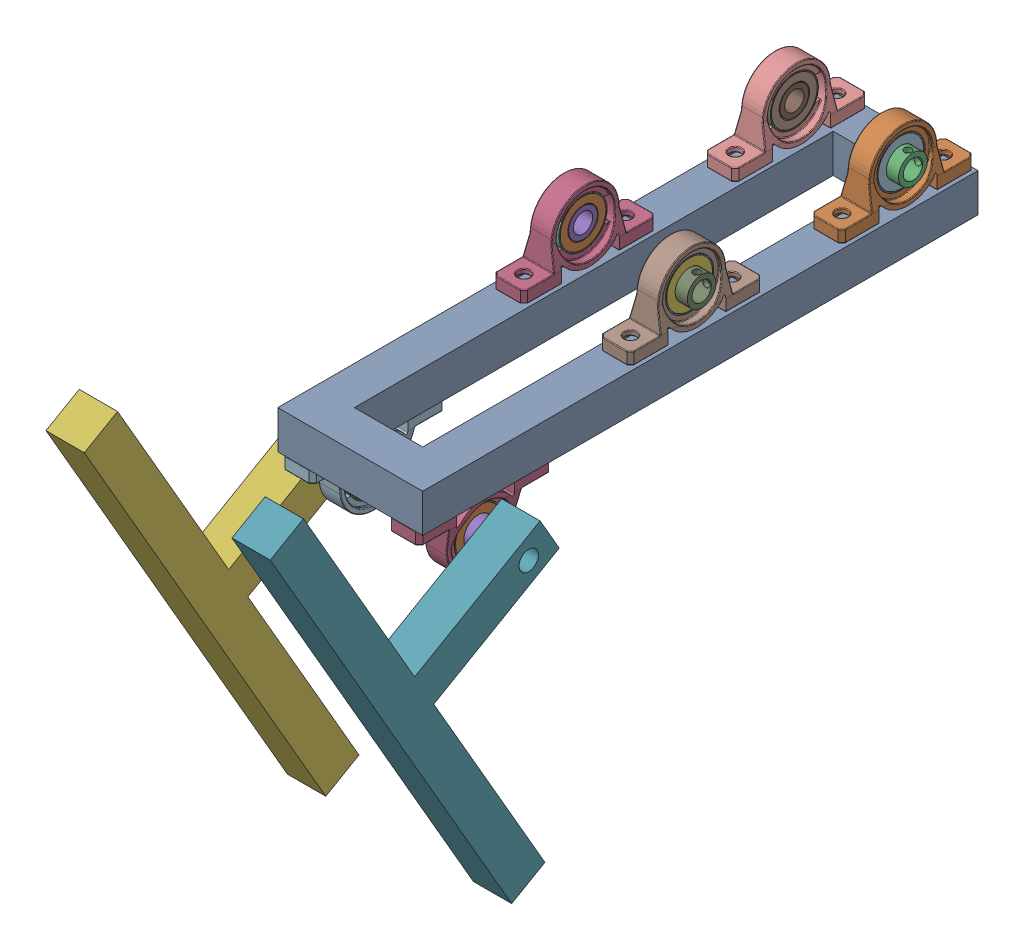
SolidWorks assembly Mirrorroller_tensioner1, configuration Default. Lengths in mm.
Overall size (92.88 211.14 309.55).
9 component instances, 3 part files, 12 mates.
Components (placement in the parent):
- Mirrorroller_tensioner-1: Mirrorroller_tensioner [Default] at (-40.6979 7.0705 -11.2795) size (60 15.88 230)
- Mirror8mm İç Çap - Rulmanlı Yatak-1: Mirror8mm İç Çap - Rulmanlı Yatak [Varsayılan] at (-62.7604 22.9455 -11.2795) x (0 0 1) z (-1 0 0) size (55 28.5 15.02)
- Mirror8mm İç Çap - Rulmanlı Yatak-2: Mirror8mm İç Çap - Rulmanlı Yatak [Varsayılan] at (-18.6354 22.9455 -11.2795) x (0 0 -1) z (1 0 0) size (55 28.5 15.02)
- Mirror8mm İç Çap - Rulmanlı Yatak-3: Mirror8mm İç Çap - Rulmanlı Yatak [Varsayılan] at (-62.7604 7.0705 76.2205) x (0 0 -1) z (-1 0 0) size (55 28.5 15.02)
- Mirror8mm İç Çap - Rulmanlı Yatak-4: Mirror8mm İç Çap - Rulmanlı Yatak [Varsayılan] at (-18.6354 7.0705 76.2205) x (0 0 1) z (1 0 0) size (55 28.5 15.02)
- Mirrorroller_pivot-1: Mirrorroller_pivot [Default] at (-87.1354 -36.3983 126.3958) x (1 0 0) z (0 0.866025 0.5) size (15.88 75.88 200)
- Mirrorroller_pivot-2: Mirrorroller_pivot [Default] at (5.7396 -36.3983 126.3958) x (-1 0 0) z (0 -0.866025 -0.5) size (15.88 75.88 200)
- Mirror8mm İç Çap - Rulmanlı Yatak-5: Mirror8mm İç Çap - Rulmanlı Yatak [Varsayılan] at (-62.7604 22.9455 -98.7795) x (0 0 1) z (-1 0 0) size (55 28.5 15.02)
- Mirror8mm İç Çap - Rulmanlı Yatak-6: Mirror8mm İç Çap - Rulmanlı Yatak [Varsayılan] at (-18.6354 22.9455 -98.7795) x (0 0 -1) z (1 0 0) size (55 28.5 15.02)
Mates (geometry in assembly coordinates):
- Coincident1: coincident anti-aligned: plane of Mirrorroller_tensioner-1 through (-40.6979 22.9455 -11.2795) normal (0 1 0); plane of Mirror8mm İç Çap - Rulmanlı Yatak-1 through (-56.2604 22.9455 -38.7795) normal (0 -1 0)
- Width1: width anti-aligned: plane of Mirror8mm İç Çap - Rulmanlı Yatak-1 through (-56.2604 27.9455 -38.7795) normal (1 0 0); plane of Mirrorroller_tensioner-1 through (-69.2604 27.9455 -38.7795) normal (-1 0 0); plane of Mirror8mm İç Çap - Rulmanlı Yatak-1 through (-70.6979 22.9455 103.7205) normal (-1 0 0); plane of Mirrorroller_tensioner-1 through (-54.8229 22.9455 87.8455) normal (1 0 0)
- Coincident2: coincident aligned: plane of Mirrorroller_tensioner-1 through (-70.6979 22.9455 103.7205) normal (0 0 1); plane of Mirror8mm İç Çap - Rulmanlı Yatak-3 through (-62.7604 7.0705 103.7205) normal (0 0 1)
- Coincident3: coincident anti-aligned: plane of Mirrorroller_tensioner-1 through (-40.6979 7.0705 -11.2795) normal (0 -1 0); plane of Mirror8mm İç Çap - Rulmanlı Yatak-3 through (-56.2604 7.0705 103.7205) normal (0 1 0)
- Width2: width anti-aligned: plane of Mirror8mm İç Çap - Rulmanlı Yatak-3 through (-69.2604 2.0705 103.7205) normal (-1 0 0); plane of Mirrorroller_tensioner-1 through (-56.2604 2.0705 103.7205) normal (1 0 0); plane of Mirror8mm İç Çap - Rulmanlı Yatak-3 through (-54.8229 22.9455 87.8455) normal (1 0 0); plane of Mirrorroller_tensioner-1 through (-70.6979 22.9455 103.7205) normal (-1 0 0)
- Concentric1: concentric aligned: cylinder of Mirror8mm İç Çap - Rulmanlı Yatak-3 through (-71.2604 -7.4295 76.2205) axis (1 0 0) radius 4; cylinder of Mirrorroller_pivot-1 through (-87.1354 -7.4295 76.2205) axis (1 0 0) radius 4
- Coincident4: coincident anti-aligned: plane of Mirror8mm İç Çap - Rulmanlı Yatak-3 through (-71.2604 -7.4295 76.2205) normal (-1 0 0); plane of Mirrorroller_pivot-1 through (-71.2604 -36.3983 126.3958) normal (1 0 0)
- Width3: width anti-aligned: plane of Mirror8mm İç Çap - Rulmanlı Yatak-1 through (-62.7604 22.9455 16.2205) normal (0 0 1); plane of Mirrorroller_tensioner-1 through (-62.7604 22.9455 -38.7795) normal (0 0 -1); plane of Mirror8mm İç Çap - Rulmanlı Yatak-1 through (-70.6979 22.9455 -126.2795) normal (0 0 -1); plane of Mirrorroller_tensioner-1 through (-70.6979 22.9455 103.7205) normal (0 0 1)
- Angle1: planar angle = 1.047198 rad anti-aligned: plane of Mirrorroller_pivot-1 through (-71.2604 -32.4295 119.5217) normal (0 0.5 -0.866025); plane of Mirrorroller_tensioner-1 through (-40.6979 7.0705 -11.2795) normal (0 -1 0)
- Coincident5: coincident anti-aligned: plane of Mirrorroller_tensioner-1 through (-40.6979 22.9455 -11.2795) normal (0 1 0); plane of Mirror8mm İç Çap - Rulmanlı Yatak-5 through (-56.2604 22.9455 -126.2795) normal (0 -1 0)
- Width4: width anti-aligned: plane of Mirror8mm İç Çap - Rulmanlı Yatak-5 through (-69.2604 27.9455 -126.2795) normal (-1 0 0); plane of Mirrorroller_tensioner-1 through (-56.2604 27.9455 -126.2795) normal (1 0 0); plane of Mirror8mm İç Çap - Rulmanlı Yatak-5 through (-54.8229 22.9455 87.8455) normal (1 0 0); plane of Mirrorroller_tensioner-1 through (-70.6979 22.9455 103.7205) normal (-1 0 0)
- Coincident6: coincident aligned: plane of Mirrorroller_tensioner-1 through (-70.6979 22.9455 -126.2795) normal (0 0 -1); plane of Mirror8mm İç Çap - Rulmanlı Yatak-5 through (-62.7604 22.9455 -126.2795) normal (0 0 -1)
